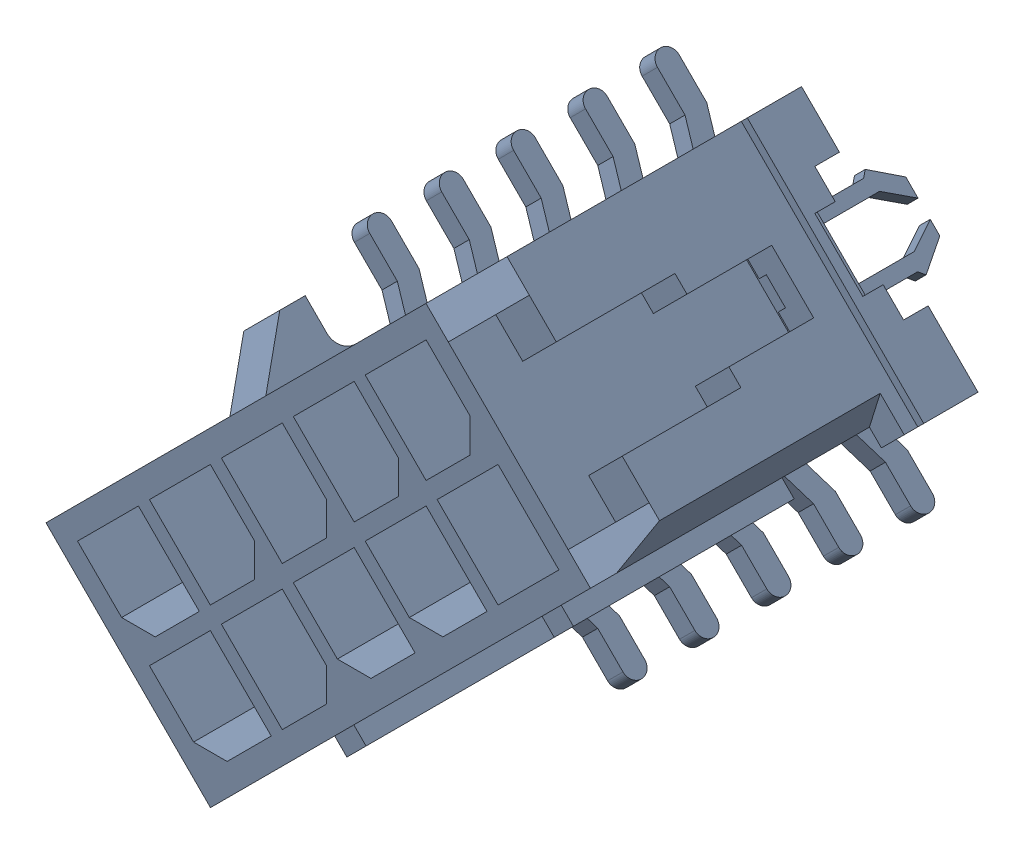
SolidWorks assembly Kanaloa_v2.0.0_Loko_14, configuration Default. Lengths in mm.
Overall size (21.46 21.46 11.91).
2 component instances, 1 part files, 0 mates.
Components (placement in the parent):
- 430451016-1: 430451016 [Default] at (172.7454 56.1341 4.953) x (0.707107 0.707107 0) z (0 0 1) size (19.15 11.2 11.91)
  - Open CASCADE STEP translator 6.2 1.28.1.1-1: Open CASCADE STEP translator 6.2 1.28.1.1 [Default] at origin size (19.15 11.2 11.91)
